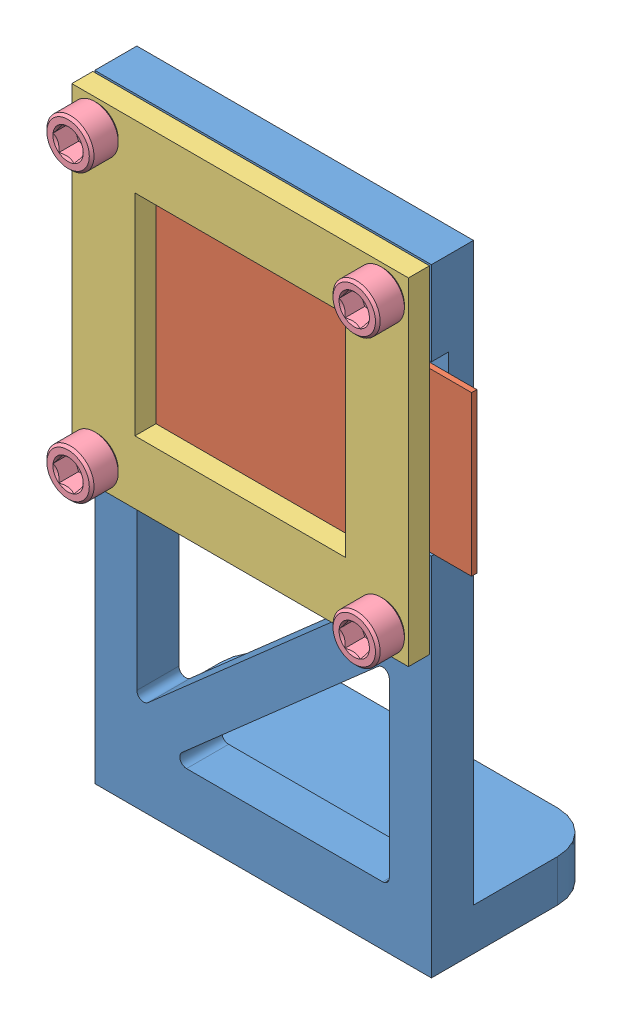
SolidWorks assembly Flat-Field Assembly, configuration Default. Lengths in mm.
Overall size (28.99 39.03 16.73).
7 component instances, 4 part files, 14 mates.
Components (placement in the parent):
- EL Panel Mount-1: EL Panel Mount [Default] at (3.3549 31.0776 38.5978) size (25.4 38.61 12.7)
- EL Panel-1: EL Panel [Default] at (3.3549 31.0776 38.3438) size (25.4 19.05 0.4)
- EL Panel Retainer-1: EL Panel Retainer [Default] at (3.3549 31.0776 38.7438) size (25.4 25.4 1.59)
- 98511A111_LIGHTWEIGHT ALUMINUM SOCKET HEAD CAP SCREW-1: 98511A111_LIGHTWEIGHT ALUMINUM SOCKET HEAD CAP SCREW [98511A111] at (-7.4401 20.2826 35.5688) x (-0.923728 -0.383049 0) z (0 0 -1) size (3.56 3.56 7.46)
- 98511A111_LIGHTWEIGHT ALUMINUM SOCKET HEAD CAP SCREW-2: 98511A111_LIGHTWEIGHT ALUMINUM SOCKET HEAD CAP SCREW [98511A111] at (14.1499 20.2826 35.5688) x (-0.923728 -0.383049 0) z (0 0 -1) size (3.56 3.56 7.46)
- 98511A111_LIGHTWEIGHT ALUMINUM SOCKET HEAD CAP SCREW-3: 98511A111_LIGHTWEIGHT ALUMINUM SOCKET HEAD CAP SCREW [98511A111] at (14.1499 41.8726 35.5688) x (-0.923728 -0.383049 0) z (0 0 -1) size (3.56 3.56 7.46)
- 98511A111_LIGHTWEIGHT ALUMINUM SOCKET HEAD CAP SCREW-4: 98511A111_LIGHTWEIGHT ALUMINUM SOCKET HEAD CAP SCREW [98511A111] at (-7.4401 41.8726 35.5688) x (-0.923728 -0.383049 0) z (0 0 -1) size (3.56 3.56 7.46)
Mates (geometry in assembly coordinates):
- Coincident1: coincident anti-aligned: plane of EL Panel Mount-1 through (3.3549 31.0776 38.3438) normal (0 0 1); plane of EL Panel-1 through (3.3549 31.0776 38.3438) normal (0 0 -1)
- Coincident2: coincident aligned: plane of EL Panel Mount-1 through (3.3549 31.0776 38.5978) normal (0 1 0); plane of EL Panel-1 through (3.3549 31.0776 38.3438) normal (0 1 0)
- Coincident3: coincident aligned: plane of EL Panel Mount-1 through (3.3549 31.0776 38.5978) normal (1 0 0); plane of EL Panel-1 through (3.3549 31.0776 38.3438) normal (1 0 0)
- Coincident4: coincident aligned: plane of EL Panel-1 through (3.3549 31.0776 38.3438) normal (0 1 0); plane of EL Panel Retainer-1 through (3.3549 31.0776 38.7438) normal (0 1 0)
- Coincident5: coincident aligned: plane of EL Panel-1 through (3.3549 31.0776 38.3438) normal (1 0 0); plane of EL Panel Retainer-1 through (3.3549 31.0776 38.7438) normal (1 0 0)
- Coincident6: coincident anti-aligned: plane of EL Panel-1 through (3.3549 31.0776 38.7438) normal (0 0 1); plane of EL Panel Retainer-1 through (3.3549 31.0776 38.7438) normal (0 0 -1)
- Coincident7: coincident anti-aligned: plane of EL Panel Retainer-1 through (3.3549 31.0776 40.3313) normal (0 0 1); plane of 98511A111_LIGHTWEIGHT ALUMINUM SOCKET HEAD CAP SCREW-4 through (-7.4401 41.8726 40.3313) normal (0 0 -1)
- Coincident8: coincident anti-aligned: plane of EL Panel Retainer-1 through (3.3549 31.0776 40.3313) normal (0 0 1); plane of 98511A111_LIGHTWEIGHT ALUMINUM SOCKET HEAD CAP SCREW-3 through (14.1499 41.8726 40.3313) normal (0 0 -1)
- Coincident9: coincident anti-aligned: plane of EL Panel Retainer-1 through (3.3549 31.0776 40.3313) normal (0 0 1); plane of 98511A111_LIGHTWEIGHT ALUMINUM SOCKET HEAD CAP SCREW-1 through (-7.4401 20.2826 40.3313) normal (0 0 -1)
- Coincident10: coincident anti-aligned: plane of EL Panel Retainer-1 through (3.3549 31.0776 40.3313) normal (0 0 1); plane of 98511A111_LIGHTWEIGHT ALUMINUM SOCKET HEAD CAP SCREW-2 through (14.1499 20.2826 40.3313) normal (0 0 -1)
- Concentric1: concentric anti-aligned: cylinder of EL Panel Retainer-1 through (-7.4401 20.2826 40.3313) axis (0 0 1) radius 1.1303; cylinder of 98511A111_LIGHTWEIGHT ALUMINUM SOCKET HEAD CAP SCREW-1 through (-7.4401 20.2826 42.5157) axis (0 0 -1) radius 1.778
- Concentric2: concentric anti-aligned: cylinder of EL Panel Retainer-1 through (14.1499 20.2826 40.3313) axis (0 0 1) radius 1.1303; cylinder of 98511A111_LIGHTWEIGHT ALUMINUM SOCKET HEAD CAP SCREW-2 through (14.1499 20.2826 42.5157) axis (0 0 -1) radius 1.778
- Concentric3: concentric anti-aligned: cylinder of EL Panel Retainer-1 through (-7.4401 41.8726 40.3313) axis (0 0 1) radius 1.1303; cylinder of 98511A111_LIGHTWEIGHT ALUMINUM SOCKET HEAD CAP SCREW-4 through (-7.4401 41.8726 42.5157) axis (0 0 -1) radius 1.778
- Concentric4: concentric anti-aligned: cylinder of EL Panel Retainer-1 through (14.1499 41.8726 40.3313) axis (0 0 1) radius 1.1303; cylinder of 98511A111_LIGHTWEIGHT ALUMINUM SOCKET HEAD CAP SCREW-3 through (14.1499 41.8726 42.5157) axis (0 0 -1) radius 1.778
